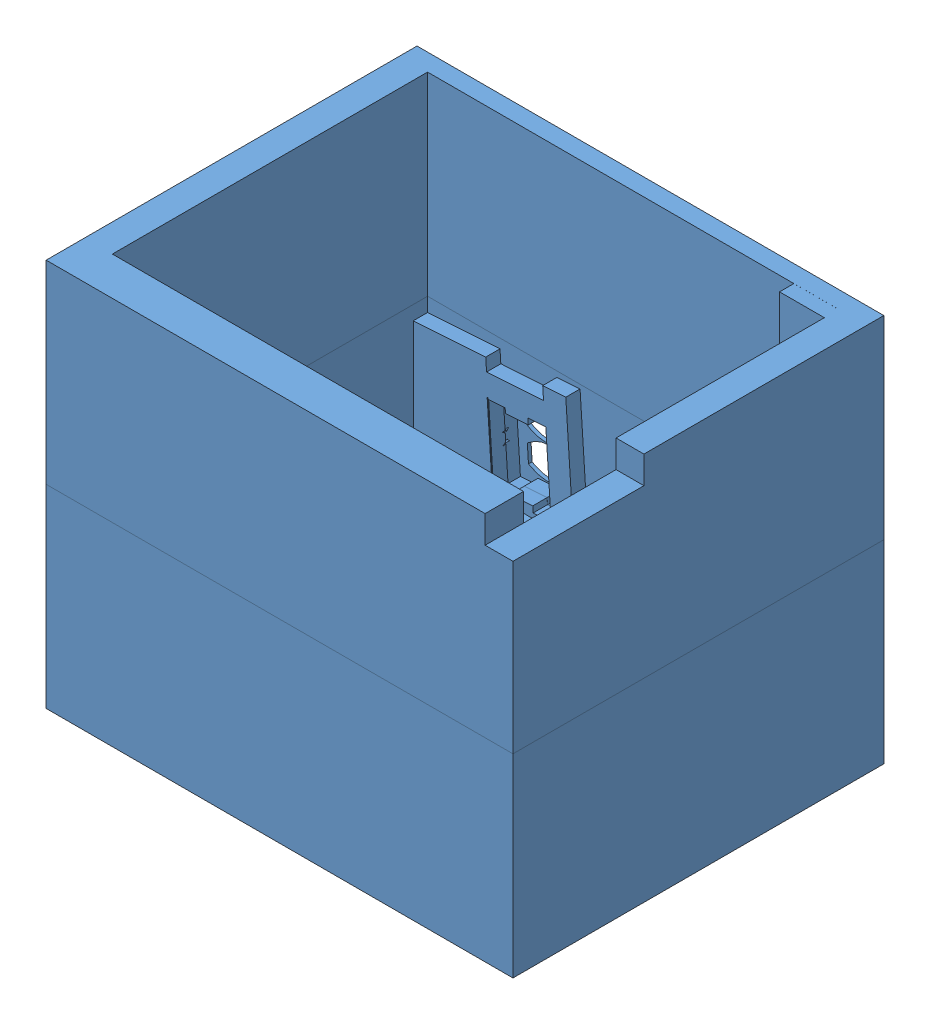
SolidWorks assembly box_r5_with_breakout_file_shrinking, configuration Default. Lengths in mm.
Overall size (49.01 34 33.88).
2 component instances, 2 part files, 2 mates.
Components (placement in the parent):
- double sensor holder_r5_pre_shrink-1: double sensor holder_r5_pre_shrink [Default] at (-26.8612 30.8435 -15.2357) size (49.01 34 33.88)
- encoderBreakout_f-1: encoderBreakout_f [Default] at (-42.9928 31.6435 -3.7637) x (1 0 0) z (0 1 0) size (32.13 21.5 8.45)
Mates (geometry in assembly coordinates):
- Coincident1: coincident anti-aligned: plane of double sensor holder_r5_pre_shrink-1 through (-26.8612 30.8435 -15.2357) normal (0 1 0); plane of encoderBreakout_f-1 through (-11.1128 30.8435 -25.2087) normal (0 -1 0)
- Concentric1: concentric: circle of double sensor holder_r5_pre_shrink-1; circle of encoderBreakout_f-1
